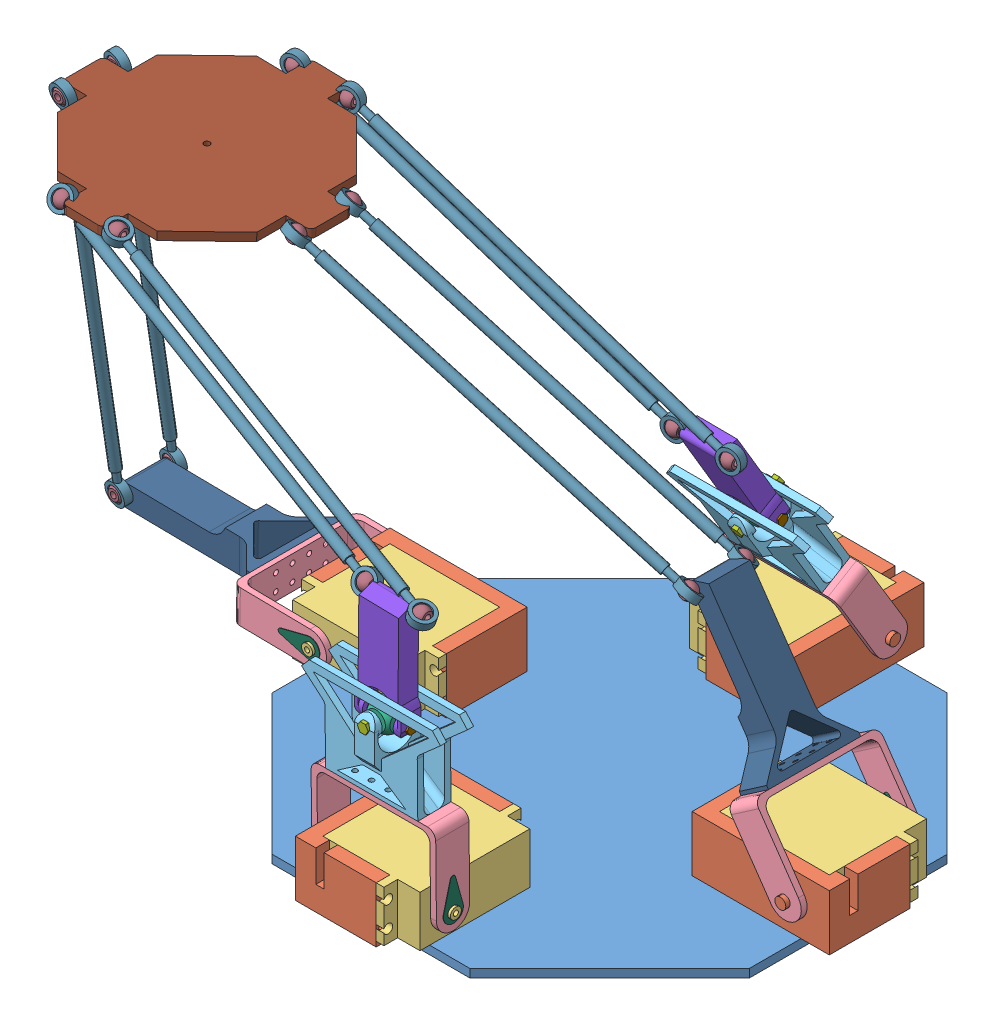
SolidWorks assembly asm(backup2), configuration 기본. Lengths in mm.
Overall size (442.04 257.52 321.27).
66 component instances, 15 part files, 154 mates.
Components (placement in the parent):
- delta_base_-1: delta_base_ [기본] at (16.2815 -22.3997 221) size (287.2 5 287.2)
- servobracket1_-1: servobracket1_ [기본] at (8418.954 -14.3997 21660.4366) x (0 0 -1) z (0 1 0) size (82.55 54.75 33.48)
- servobracket1_-2: servobracket1_ [기본] at (-21423.155 -14.3997 8623.6725) x (1 0 0) z (0 1 0) size (82.55 54.75 33.48)
- servobracket1_-3: servobracket1_ [기본] at (-8386.3909 -14.3997 -21218.4366) x (0 0 1) z (0 1 0) size (82.55 54.75 33.48)
- servobracket1_-4: servobracket1_ [기본] at (21455.7181 -14.3997 -8181.6725) x (-1 0 0) z (0 1 0) size (82.55 54.75 33.48)
- servo_drive_HV2060MG-1: servo_drive_HV2060MG [기본] at (-103.0792 0.8403 200.815) x (-1 0 0) z (0 0 1) size (82.55 30.48 64.98)
- servo_drive_HV2060MG-2: servo_drive_HV2060MG [기본] at (36.4665 0.8403 101.6393) x (0 0 -1) z (-1 0 0) size (82.55 30.48 64.98)
- servo_drive_HV2060MG-3: servo_drive_HV2060MG [기본] at (135.6423 0.8403 241.185) x (1 0 0) z (0 0 -1) size (82.55 30.48 64.98)
- servo_drive_HV2060MG-4: servo_drive_HV2060MG [기본] at (-3.9035 0.8403 340.3607) x (0 0 1) z (1 0 0) size (82.55 30.48 64.98)
- servobracket2_-1: servobracket2_ [기본] at (20.8415 47.838 358.7486) x (1 0 0) z (0 0.009952 -0.99995) size (75 57 20)
- servobracket2_-2: servobracket2_ [기본] at (11.7215 41.0925 107.9835) x (-1 0 0) z (0 -0.516264 0.85643) size (75 57 20)
- univ_link1-1: univ_link1 [기본] at (14.8415 70.128 358.9705) x (0 -0.009952 0.99995) z (1 0 0) size (28.84 52.05 83.6)
- univ_link1-2: univ_link1 [기본] at (5.7215 60.1833 119.4916) x (0 -0.516264 0.85643) z (1 0 0) size (28.84 52.05 83.6)
- ball-1: ball [기본] at (20.8415 85.1323 359.1198) x (-0.999788 0.020606 0.000205) z (0 0.009952 -0.99995) size (24 24 18)
- ball-2: ball [기본] at (11.7215 73.034 127.2381) x (0.999789 -0.017578 -0.010596) z (0 -0.516264 0.85643) size (24 24 18)
- univ_bolt_-1: univ_bolt_ [기본] at (20.8415 85.2815 344.1207) x (1 0 0) z (0 -0.99995 -0.009952) size (6.46 12 5.59)
- univ_bolt_-2: univ_bolt_ [기본] at (11.7215 65.29 140.0848) x (0.5 -0.74169 -0.447097) z (0.866025 0.428215 0.258132) size (6.46 12 5.59)
- univ_bolt_-3: univ_bolt_ [기본] at (20.8415 84.983 374.1193) x (1 0 0) z (0 0.99995 0.009952) size (6.46 12 5.59)
- univ_bolt_-4: univ_bolt_ [기본] at (11.7215 80.7779 114.3919) x (0.5 0.74169 0.447097) z (0.866025 -0.428215 -0.258132) size (6.46 12 5.59)
- univ_link2-3: univ_link2 [기본] at (12.0407 82.7718 140.114) x (-0.999789 0.017578 0.010596) z (0 0.516264 -0.85643) size (28.56 68.77 12)
- univ_bolt2_-1: univ_bolt2_ [기본] at (26.7297 72.7702 127.0791) x (0 -0.516264 0.85643) z (-0.020525 -0.856249 -0.516155) size (6.46 12 5.59)
- univ_bolt2_-2: univ_bolt2_ [기본] at (-3.264 73.2975 127.397) x (0 0.516264 -0.85643) z (-0.020525 -0.856249 -0.516155) size (6.46 12 5.59)
- univ_link2-4: univ_link2 [기본] at (21.1615 100.1783 353.2692) x (0.999788 -0.020606 -0.000205) z (0 -0.009952 0.99995) size (28.56 68.77 12)
- univ_bolt2_-3: univ_bolt2_ [기본] at (5.856 85.4411 359.1229) x (0 0.009952 -0.99995) z (-0.020607 -0.999738 -0.00995) size (6.46 12 5.59)
- univ_bolt2_-4: univ_bolt2_ [기본] at (35.8496 84.823 359.1167) x (0 -0.009952 0.99995) z (-0.020607 -0.999738 -0.00995) size (6.46 12 5.59)
- servobracket2_-3: servobracket2_ [기본] at (-167.995 1.4804 225.56) x (0 0 1) z (0.013619 0.999907 0) size (75 57 20)
- servobracket2_-4: servobracket2_ [기본] at (126.8456 39.5083 216.44) x (0 0 -1) z (-0.822723 -0.568443 0) size (75 57 20)
- link1_-1: link1_ [기본] at (118.6184 33.8239 244.19) x (0 0 -1) z (0.568443 -0.822723 0) size (55.5 20 93)
- link1_-2: link1_ [기본] at (-167.8588 11.4795 197.81) x (0 0 1) z (0.999907 -0.013619 0) size (55.5 20 93)
- delta_end_-1: delta_end_ [기본] at (-187.6375 228.1369 259.3603) x (-0.999789 0.020532 0) z (0 0 1) size (150 5 150)
- link_bridge_-1: link_bridge_ [기본] at (75.6845 113.5552 216.4377) x (-1 0 0) z (0 1 0) size (4.5 28.5 4.5)
- bearing-1: bearing [기본] at (75.6845 113.5552 200.0127) x (0 1 0) z (1 0 0) size (9.35 6.85 9.35)
- link_bridge_-2: link_bridge_ [기본] at (-117.7035 224.2001 259.3603) x (0.013819 0.999905 0) z (0.999905 -0.013819 0) size (4.5 28.5 4.5)
- bearing-2: bearing [기본] at (-117.7035 224.2001 242.9353) x (0.999983 -0.005841 0) z (-0.005841 -0.999983 0) size (9.35 6.85 9.35)
- bearing-3: bearing [기본] at (75.6845 113.5552 232.8627) x (1 0 0) z (0 -1 0) size (9.35 6.85 9.35)
- bearing-4: bearing [기본] at (-117.7035 224.2001 275.7853) x (0 -1 0) z (1 0 0) size (9.35 6.85 9.35)
- rod-1: rod [기본] at (75.6845 113.5552 232.8627) x (-0.447003 -0.491287 -0.747547) z (-0.852305 0.487638 0.18917) size (13.45 6 240.35)
- rod-2: rod [기본] at (-117.7035 224.2001 242.9353) x (0.430843 0.449472 0.782527) z (0.852305 -0.487638 -0.18917) size (13.45 6 240.35)
- link_bridge_-3: link_bridge_ [기본] at (-257.674 227.0746 259.3603) x (0.064888 0.997893 0) z (0.997893 -0.064888 0) size (4.5 28.5 4.5)
- bearing-5: bearing [기본] at (-257.674 227.0746 275.7853) x (-0.114329 0.993443 0) z (-0.993443 -0.114329 0) size (9.35 6.85 9.35)
- bearing-6: bearing [기본] at (-257.674 227.0746 242.9353) x (1 0 0) z (0 -1 0) size (9.35 6.85 9.35)
- link_bridge_-4: link_bridge_ [기본] at (-257.9888 2.7062 225.5623) x (1 0 0) z (0 -1 0) size (4.5 28.5 4.5)
- bearing-7: bearing [기본] at (-257.9888 2.7062 209.1373) x (1 0 0) z (0 -1 0) size (9.35 6.85 9.35)
- bearing-8: bearing [기본] at (-257.9888 2.7062 241.9873) x (-1 0 0) z (0 -1 0) size (9.35 6.85 9.35)
- rod-3: rod [기본] at (-257.674 227.0746 242.9353) x (0.986649 -0.025612 0.160834) z (-0.001387 -0.988843 -0.148956) size (13.45 6 240.35)
- rod-4: rod [기본] at (-257.9888 2.7062 241.9873) x (-0.992547 0.019512 -0.120288) z (0.001387 0.988843 0.148956) size (13.45 6 240.35)
- link_bridge_-5: link_bridge_ [기본] at (-187.6888 225.6374 189.3603) x (0.020532 0.999789 0) z (0 0 1) size (4.5 28.5 4.5)
- link_bridge_-6: link_bridge_ [기본] at (12.4542 122.668 160.6609) x (0.019047 0.986952 0.159885) z (-0.007648 0.160053 -0.987079) size (4.5 28.5 4.5)
- bearing-9: bearing [기본] at (-204.1103 225.9746 189.3603) x (-0.000218 -0.010596 -0.999944) z (-0.020531 -0.999733 0.010598) size (9.35 6.85 9.35)
- bearing-10: bearing [기본] at (-171.2673 225.3002 189.3603) x (0.017394 0.846974 0.531349) z (-0.01091 -0.531237 0.847153) size (9.35 6.85 9.35)
- bearing-11: bearing [기본] at (-3.9673 122.9568 160.8349) x (-0.019047 -0.986952 -0.159885) z (0.007648 -0.160053 0.987079) size (9.35 6.85 9.35)
- bearing-12: bearing [기본] at (28.8758 122.3793 160.4868) x (0.019047 0.986952 0.159885) z (0.007648 -0.160053 0.987079) size (9.35 6.85 9.35)
- rod-5: rod [기본] at (-204.1103 225.9746 189.3603) x (0.449518 0.89099 -0.0638) z (0.882076 -0.454023 -0.125718) size (13.45 6 240.35)
- rod-6: rod [기본] at (28.8758 122.3793 160.4868) x (-0.439311 -0.889519 0.125547) z (-0.882076 0.453596 0.127252) size (13.45 6 240.35)
- link_bridge_-8: link_bridge_ [기본] at (22.5897 144.9013 356.7145) x (0.020602 0.999328 0.030308) z (-0.00042 -0.030306 0.999541) size (4.5 28.5 4.5)
- bearing-13: bearing [기본] at (39.0112 144.5628 356.7111) x (0.020037 0.969771 0.243194) z (-0.004812 -0.243147 0.969978) size (9.35 6.85 9.35)
- bearing-15: bearing [기본] at (6.1682 145.2397 356.7179) x (-0.020602 -0.999327 -0.03034) z (-0.00042 -0.030338 0.99954) size (9.35 6.85 9.35)
- rod-8: rod [기본] at (39.0112 144.5628 356.7111) x (-0.131805 -0.007485 0.991247) z (-0.926745 0.355828 -0.120541) size (13.45 6 240.35)
- rod-9: rod [기본] at (6.1682 145.2397 356.7179) x (-0.362907 -0.764853 0.532257) z (-0.926745 0.355817 -0.120571) size (13.45 6 240.35)
- servobracket3_-2: servobracket3_ [기본] at (153.5748 0.8403 177.7076) x (-0.822723 -0.568443 0) z (-0.568443 0.822723 0) size (12 5 24.89)
- servobracket3_-3: servobracket3_ [기본] at (54.5739 0.8403 358.2932) x (0 -0.009952 0.99995) z (0 0.99995 0.009952) size (12 5 24.89)
- servobracket3_-4: servobracket3_ [기본] at (-22.0109 0.8403 83.7068) x (0 0.516264 -0.85643) z (0 0.85643 0.516264) size (12 5 24.89)
- servobracket3_-5: servobracket3_ [기본] at (-121.0117 0.8403 259.2924) x (-0.013619 -0.999907 0) z (-0.999907 0.013619 0) size (12 5 24.89)
- link_bridge_-9: link_bridge_ [기본] at (-187.6888 225.6374 329.3603) x (0.020532 0.999789 0) z (0 0 -1) size (4.5 28.5 4.5)
- bearing-17: bearing [기본] at (-171.2673 225.3002 329.3603) x (0.019936 0.97077 0.239183) z (0.004911 0.239133 -0.970974) size (9.35 6.85 9.35)
- bearing-18: bearing [기본] at (-204.1103 225.9746 329.3603) x (0.018656 0.908414 0.417655) z (-0.008575 -0.417567 0.908606) size (9.35 6.85 9.35)
Mates (geometry in assembly coordinates):
- 동심1: concentric anti-aligned: cylinder of delta_base_-1 through (11.2815 -17.3997 82.46) axis (0 -1 0) radius 1.5; cylinder of servobracket1_-1 through (11.2815 -17.3997 82.46) axis (0 1 0) radius 1.5
- 동심2: concentric anti-aligned: cylinder of delta_base_-1 through (21.2815 -17.3997 92.46) axis (0 -1 0) radius 1.5; cylinder of servobracket1_-1 through (21.2815 -17.3997 92.46) axis (0 1 0) radius 1.5
- 일치1: coincident anti-aligned: plane of delta_base_-1 through (16.2815 -17.3997 221) normal (0 1 0); plane of servobracket1_-1 through (8418.954 -17.3997 21660.4366) normal (0 -1 0)
- 동심3: concentric anti-aligned: cylinder of delta_base_-1 through (154.8215 -17.3997 216) axis (0 -1 0) radius 1.5; cylinder of servobracket1_-2 through (154.8215 -17.3997 216) axis (0 1 0) radius 1.5
- 동심4: concentric anti-aligned: cylinder of delta_base_-1 through (144.8215 -17.3997 226) axis (0 -1 0) radius 1.5; cylinder of servobracket1_-2 through (144.8215 -17.3997 226) axis (0 1 0) radius 1.5
- 일치4: coincident anti-aligned: plane of delta_base_-1 through (16.2815 -17.3997 221) normal (0 1 0); plane of servobracket1_-2 through (-21423.155 -17.3997 8623.6725) normal (0 -1 0)
- 동심5: concentric anti-aligned: cylinder of delta_base_-1 through (21.2815 -17.3997 359.54) axis (0 -1 0) radius 1.5; cylinder of servobracket1_-3 through (21.2815 -17.3997 359.54) axis (0 1 0) radius 1.5
- 동심6: concentric anti-aligned: cylinder of delta_base_-1 through (11.2815 -17.3997 349.54) axis (0 -1 0) radius 1.5; cylinder of servobracket1_-3 through (11.2815 -17.3997 349.54) axis (0 1 0) radius 1.5
- 일치5: coincident anti-aligned: plane of delta_base_-1 through (16.2815 -17.3997 221) normal (0 1 0); plane of servobracket1_-3 through (-8386.3909 -17.3997 -21218.4366) normal (0 -1 0)
- 동심7: concentric anti-aligned: cylinder of delta_base_-1 through (-122.2585 -17.3997 226) axis (0 -1 0) radius 1.5; cylinder of servobracket1_-4 through (-122.2585 -17.3997 226) axis (0 1 0) radius 1.5
- 동심8: concentric anti-aligned: cylinder of delta_base_-1 through (-112.2585 -17.3997 216) axis (0 -1 0) radius 1.5; cylinder of servobracket1_-4 through (-112.2585 -17.3997 216) axis (0 1 0) radius 1.5
- 일치6: coincident anti-aligned: plane of delta_base_-1 through (16.2815 -17.3997 221) normal (0 1 0); plane of servobracket1_-4 through (21455.7181 -17.3997 -8181.6725) normal (0 -1 0)
- 일치7: coincident anti-aligned: plane of servobracket1_-4 through (-70.0592 16.0803 241.1804) normal (-1 0 0); plane of servo_drive_HV2060MG-1 through (-70.0592 16.0803 241.1904) normal (1 0 0)
- 일치8: coincident anti-aligned: plane of servobracket1_-4 through (-70.0592 16.0803 200.815) normal (0 0 1); plane of servo_drive_HV2060MG-1 through (-103.0792 0.8403 200.815) normal (0 0 -1)
- 일치9: coincident anti-aligned: plane of servobracket1_-4 through (21455.7181 -14.3997 -8181.6725) normal (0 1 0); plane of servo_drive_HV2060MG-1 through (-136.0992 -14.3997 241.1904) normal (0 -1 0)
- 일치10: coincident anti-aligned: plane of servobracket1_-1 through (-3.8989 16.0803 134.6593) normal (0 0 -1); plane of servo_drive_HV2060MG-2 through (-3.9089 16.0803 134.6593) normal (0 0 1)
- 일치11: coincident anti-aligned: plane of servobracket1_-1 through (36.4665 16.0803 134.6593) normal (-1 0 0); plane of servo_drive_HV2060MG-2 through (36.4665 0.8403 101.6393) normal (1 0 0)
- 일치12: coincident anti-aligned: plane of servobracket1_-1 through (8418.954 -14.3997 21660.4366) normal (0 1 0); plane of servo_drive_HV2060MG-2 through (-3.9089 -14.3997 68.6193) normal (0 -1 0)
- 일치13: coincident anti-aligned: plane of servobracket1_-2 through (102.6223 16.0803 200.8196) normal (1 0 0); plane of servo_drive_HV2060MG-3 through (102.6223 16.0803 200.8096) normal (-1 0 0)
- 일치14: coincident anti-aligned: plane of servobracket1_-2 through (102.6223 16.0803 241.185) normal (0 0 -1); plane of servo_drive_HV2060MG-3 through (135.6423 0.8403 241.185) normal (0 0 1)
- 일치15: coincident anti-aligned: plane of servobracket1_-2 through (-21423.155 -14.3997 8623.6725) normal (0 1 0); plane of servo_drive_HV2060MG-3 through (168.6623 -14.3997 200.8096) normal (0 -1 0)
- 일치16: coincident anti-aligned: plane of servobracket1_-3 through (36.4619 16.0803 307.3407) normal (0 0 1); plane of servo_drive_HV2060MG-4 through (36.4719 16.0803 307.3407) normal (0 0 -1)
- 일치17: coincident anti-aligned: plane of servobracket1_-3 through (-3.9035 16.0803 307.3407) normal (1 0 0); plane of servo_drive_HV2060MG-4 through (-3.9035 0.8403 340.3607) normal (-1 0 0)
- 일치18: coincident anti-aligned: plane of servobracket1_-3 through (-8386.3909 -14.3997 -21218.4366) normal (0 1 0); plane of servo_drive_HV2060MG-4 through (36.4719 -14.3997 373.3807) normal (0 -1 0)
- 동심12: concentric aligned: circle of servobracket1_-3; cylinder of servobracket2_-1 through (-12.1585 0.8403 358.2809) axis (-1 0 0) radius 3.3
- 일치19: coincident anti-aligned: plane of servobracket1_-3 through (-12.1585 16.0803 381.6357) normal (-1 0 0); plane of servobracket2_-1 through (-12.1585 -9.2587 368.1809) normal (1 0 0)
- 동심13: concentric aligned: circle of servobracket1_-1; cylinder of servobracket2_-2 through (44.7215 0.8403 83.7191) axis (1 0 0) radius 3.3
- 일치20: coincident anti-aligned: plane of servobracket1_-1 through (44.7215 16.0803 60.3643) normal (1 0 0); plane of servobracket2_-2 through (44.7215 -2.5613 69.9922) normal (-1 0 0)
- 동심14: concentric anti-aligned: cylinder of servobracket2_-1 through (15.8415 45.7884 363.7285) axis (0 0.99995 0.009952) radius 1.5; cylinder of univ_link1-1 through (15.8415 50.7881 363.7782) axis (0 -0.99995 -0.009952) radius 1.5
- 동심15: concentric anti-aligned: cylinder of servobracket2_-1 through (25.8415 45.8879 353.729) axis (0 0.99995 0.009952) radius 1.5; cylinder of univ_link1-1 through (25.8415 50.8876 353.7787) axis (0 -0.99995 -0.009952) radius 1.5
- 일치22: coincident anti-aligned: plane of servobracket2_-1 through (20.8415 47.838 358.7486) normal (0 0.99995 0.009952); plane of univ_link1-1 through (-6.9085 47.7385 368.7481) normal (0 -0.99995 -0.009952)
- 동심16: concentric anti-aligned: cylinder of servobracket2_-2 through (6.7215 36.7984 111.2331) axis (0 0.85643 0.516264) radius 1.5; cylinder of univ_link1-2 through (6.7215 41.0805 113.8144) axis (0 -0.85643 -0.516264) radius 1.5
- 동심17: concentric anti-aligned: cylinder of servobracket2_-2 through (16.7215 41.961 102.6688) axis (0 0.85643 0.516264) radius 1.5; cylinder of univ_link1-2 through (16.7215 46.2432 105.2502) axis (0 -0.85643 -0.516264) radius 1.5
- 일치23: coincident anti-aligned: plane of servobracket2_-2 through (11.7215 41.0925 107.9835) normal (0 0.85643 0.516264); plane of univ_link1-2 through (-16.0285 35.9299 116.5478) normal (0 -0.85643 -0.516264)
- 일치24: coincident anti-aligned: circle of univ_link1-1; circle of ball-1
- 일치26: coincident anti-aligned: plane of univ_link1-1 through (22.4565 82.4645 346.0928) normal (0 0.99995 0.009952); plane of univ_bolt_-1 through (19.2265 82.4645 346.0928) normal (0 -0.99995 -0.009952)
- 동심18: concentric aligned: cylinder of ball-1 through (20.8415 85.0626 366.1195) axis (0 0.009952 -0.99995) radius 1.55; cylinder of univ_bolt_-1 through (20.8415 85.1621 356.1202) axis (0 0.009952 -0.99995) radius 1.55
- 일치27: coincident anti-aligned: plane of univ_link1-1 through (14.8415 70.2574 345.9713) normal (0 0.009952 -0.99995); plane of univ_bolt_-1 through (20.8415 85.2616 346.1206) normal (0 -0.009952 0.99995)
- 일치28: coincident anti-aligned: plane of univ_link1-2 through (10.1065 63.9268 136.9278) normal (0 0.85643 0.516264); plane of univ_bolt_-2 through (13.3365 63.9268 136.9278) normal (0 -0.85643 -0.516264)
- 동심19: concentric aligned: cylinder of ball-2 through (11.7215 76.6479 121.2431) axis (0 -0.516264 0.85643) radius 1.55; cylinder of univ_bolt_-2 through (11.7215 71.4851 129.8076) axis (0 -0.516264 0.85643) radius 1.55
- 일치29: coincident anti-aligned: plane of univ_link1-2 through (5.7215 53.4717 130.6253) normal (0 -0.516264 0.85643); plane of univ_bolt_-2 through (11.7215 66.3225 138.3719) normal (0 0.516264 -0.85643)
- 동심20: concentric anti-aligned: cylinder of ball-1 through (20.8415 85.0626 366.1195) axis (0 0.009952 -0.99995) radius 1.55; cylinder of univ_bolt_-3 through (20.8415 85.1024 362.1199) axis (0 -0.009952 0.99995) radius 1.55
- 일치30: coincident anti-aligned: plane of univ_link1-1 through (19.2265 82.2058 372.0915) normal (0 0.99995 0.009952); plane of univ_bolt_-3 through (22.4565 82.2058 372.0915) normal (0 -0.99995 -0.009952)
- 일치31: coincident anti-aligned: plane of univ_link1-1 through (14.8415 69.9986 371.97) normal (0 -0.009952 0.99995); plane of univ_bolt_-3 through (20.8415 85.0029 372.1194) normal (0 0.009952 -0.99995)
- 일치32: coincident anti-aligned: plane of univ_link1-2 through (13.3365 77.3497 114.6606) normal (0 0.85643 0.516264); plane of univ_bolt_-4 through (10.1065 77.3497 114.6606) normal (0 -0.85643 -0.516264)
- 동심21: concentric anti-aligned: cylinder of ball-2 through (11.7215 76.6479 121.2431) axis (0 -0.516264 0.85643) radius 1.55; cylinder of univ_bolt_-4 through (11.7215 74.5827 124.669) axis (0 0.516264 -0.85643) radius 1.55
- 일치33: coincident anti-aligned: plane of univ_link1-2 through (5.7215 66.8946 108.3582) normal (0 0.516264 -0.85643); plane of univ_bolt_-4 through (11.7215 79.7454 116.1047) normal (0 -0.516264 0.85643)
- 일치35: coincident aligned: plane of ball-2; plane of univ_link2-3
- 일치37: coincident anti-aligned: plane of univ_link2-3; plane of univ_bolt2_-1
- 일치38: coincident anti-aligned: plane of ball-2 through (2.7542 75.251 126.8231) normal (0 -0.516264 0.85643); plane of univ_bolt2_-1 through (14.763 75.0399 126.6958) normal (0 0.516264 -0.85643)
- 일치39: coincident anti-aligned: plane of ball-2 through (2.6926 71.1335 127.8439) normal (0.020525 0.856249 0.516155); plane of univ_bolt2_-1 through (14.7014 72.4711 125.1473) normal (-0.020525 -0.856249 -0.516155)
- 일치40: coincident anti-aligned: plane of univ_link2-3; plane of univ_bolt2_-1
- 일치126: coincident aligned: circle of univ_link1-2; circle of ball-2
- 일치44: coincident anti-aligned: plane of univ_link2-3; plane of univ_bolt2_-2
- 일치45: coincident anti-aligned: plane of ball-2 through (2.7542 73.7022 129.3924) normal (0 0.516264 -0.85643); plane of univ_bolt2_-2 through (8.7642 73.5965 129.3287) normal (0 -0.516264 0.85643)
- 일치46: coincident anti-aligned: plane of ball-2 through (2.6926 71.1335 127.8439) normal (0.020525 0.856249 0.516155); plane of univ_bolt2_-2 through (8.7027 71.0278 127.7802) normal (-0.020525 -0.856249 -0.516155)
- 일치47: coincident anti-aligned: plane of univ_link2-3; plane of univ_bolt2_-2
- 일치49: coincident aligned: plane of ball-1 through (29.8705 86.4315 360.6328) normal (0 0.009952 -0.99995); plane of univ_link2-4 through (6.4664 86.9111 360.6376) normal (0 0.009952 -0.99995)
- 일치50: coincident anti-aligned: plane of univ_link2-4 through (7.9132 88.2562 353.1506) normal (-0.020607 -0.999738 -0.00995); plane of univ_bolt2_-3 through (7.9132 88.2125 357.5354) normal (0.020607 0.999738 0.00995)
- 일치51: coincident anti-aligned: plane of ball-1 through (29.8705 86.4315 360.6328) normal (0 0.009952 -0.99995); plane of univ_bolt2_-3 through (17.8844 86.6785 360.6353) normal (0 -0.009952 0.99995)
- 일치52: coincident anti-aligned: plane of ball-1 through (29.8087 83.4621 357.6031) normal (0.020607 0.999738 0.00995); plane of univ_bolt2_-3 through (17.8225 83.6793 360.6054) normal (-0.020607 -0.999738 -0.00995)
- 일치53: coincident anti-aligned: plane of univ_link2-4 through (8.1645 100.4462 353.2719) normal (-0.999788 0.020606 0.000205); plane of univ_bolt2_-3 through (7.8556 85.3999 359.1225) normal (0.999788 -0.020606 -0.000205)
- 일치54: coincident anti-aligned: plane of univ_link2-4 through (33.9077 87.6768 357.5285) normal (-0.020607 -0.999738 -0.00995); plane of univ_bolt2_-4 through (33.9077 87.6446 360.7599) normal (0.020607 0.999738 0.00995)
- 일치55: coincident anti-aligned: plane of ball-1 through (29.8705 86.4614 357.633) normal (0 -0.009952 0.99995); plane of univ_bolt2_-4 through (23.8831 86.5848 357.6342) normal (0 0.009952 -0.99995)
- 일치56: coincident anti-aligned: plane of ball-1 through (29.8087 83.4621 357.6031) normal (0.020607 0.999738 0.00995); plane of univ_bolt2_-4 through (23.8213 83.5855 357.6043) normal (-0.020607 -0.999738 -0.00995)
- 일치57: coincident anti-aligned: plane of univ_link2-4 through (34.159 99.9104 353.2666) normal (0.999788 -0.020606 -0.000205); plane of univ_bolt2_-4 through (33.8501 84.8642 359.1171) normal (-0.999788 0.020606 0.000205)
- 동심22: concentric aligned: circle of servobracket1_-4; cylinder of servobracket2_-3 through (-120.9993 0.8403 192.56) axis (0 0 -1) radius 3.3
- 일치58: coincident anti-aligned: plane of servobracket1_-4 through (-144.3542 16.0803 192.56) normal (0 0 -1); plane of servobracket2_-3 through (-111.1365 -9.2949 192.56) normal (0 0 1)
- 동심23: concentric aligned: circle of servobracket1_-2; cylinder of servobracket2_-4 through (153.5624 0.8403 249.44) axis (0 0 1) radius 3.3
- 일치59: coincident anti-aligned: plane of servobracket1_-2 through (176.9173 16.0803 249.44) normal (0 0 1); plane of servobracket2_-4 through (167.4741 -1.7025 249.44) normal (0 0 -1)
- 동심24: concentric anti-aligned: cylinder of servobracket2_-4 through (132.0961 40.7051 221.44) axis (-0.568443 0.822723 0) radius 1.5; cylinder of link1_-1 through (128.117 46.4641 221.44) axis (0.568443 -0.822723 0) radius 1.5
- 동심25: concentric anti-aligned: cylinder of servobracket2_-4 through (123.8689 35.0207 211.44) axis (-0.568443 0.822723 0) radius 1.5; cylinder of link1_-1 through (119.8898 40.7797 211.44) axis (0.568443 -0.822723 0) radius 1.5
- 일치60: coincident anti-aligned: plane of servobracket2_-4 through (126.8456 39.5083 216.44) normal (-0.568443 0.822723 0); plane of link1_-1 through (135.0728 45.1927 188.69) normal (0.568443 -0.822723 0)
- 동심26: concentric anti-aligned: cylinder of servobracket2_-3 through (-166.0633 -3.5463 230.56) axis (-0.999907 0.013619 0) radius 1.5; cylinder of link1_-2 through (-173.0626 -3.451 230.56) axis (0.999907 -0.013619 0) radius 1.5
- 동심27: concentric anti-aligned: cylinder of servobracket2_-3 through (-165.9271 6.4527 220.56) axis (-0.999907 0.013619 0) radius 1.5; cylinder of link1_-2 through (-172.9264 6.5481 220.56) axis (0.999907 -0.013619 0) radius 1.5
- 일치61: coincident anti-aligned: plane of servobracket2_-3 through (-167.995 1.4804 225.56) normal (-0.999907 0.013619 0); plane of link1_-2 through (-168.1312 -8.5186 253.31) normal (0.999907 -0.013619 0)
- 동심29: concentric anti-aligned: cylinder of link1_-1 through (75.6845 113.5552 188.69) axis (0 0 1) radius 2.15; cylinder of link_bridge_-1 through (75.6845 113.5552 228.9377) axis (0 0 -1) radius 2
- 일치66: coincident anti-aligned: plane of link1_-1 through (83.913 119.2378 228.9377) normal (0 0 1); plane of link_bridge_-1 through (75.6845 113.5552 228.9377) normal (0 0 -1)
- 일치68: coincident anti-aligned: plane of link_bridge_-1 through (75.6845 113.5552 203.4377) normal (0 0 -1); plane of bearing-1 through (75.6845 113.5552 203.4377) normal (0 0 1)
- 동심30: concentric aligned: cylinder of link_bridge_-1 through (75.6845 113.5552 202.1877) axis (0 0 1) radius 1.775; cylinder of bearing-1 through (75.6845 113.5552 196.5877) axis (0 0 1) radius 1.775
- 동심31: concentric anti-aligned: cylinder of delta_end_-1 through (-117.7035 224.2001 184.3603) axis (0 0 1) radius 2; cylinder of link_bridge_-2 through (-117.7035 224.2001 271.8603) axis (0 0 -1) radius 2
- 일치70: coincident anti-aligned: plane of delta_end_-1 through (-187.7401 223.1379 271.8603) normal (0 0 1); plane of link_bridge_-2 through (-117.7035 224.2001 271.8603) normal (0 0 -1)
- 동심32: concentric aligned: cylinder of link_bridge_-2 through (-117.7035 224.2001 245.1103) axis (0 0 1) radius 1.775; cylinder of bearing-2 through (-117.7035 224.2001 239.5103) axis (0 0 1) radius 1.775
- 일치71: coincident anti-aligned: plane of link_bridge_-2 through (-117.7035 224.2001 246.3603) normal (0 0 -1); plane of bearing-2 through (-117.7035 224.2001 246.3603) normal (0 0 1)
- 동심35: concentric anti-aligned: cylinder of link_bridge_-1 through (75.6845 113.5552 230.6877) axis (0 0 -1) radius 1.775; cylinder of bearing-3 through (75.6845 113.5552 229.4377) axis (0 0 1) radius 1.775
- 일치76: coincident anti-aligned: plane of link_bridge_-1 through (75.6845 113.5552 229.4377) normal (0 0 1); plane of bearing-3 through (75.6845 113.5552 229.4377) normal (0 0 -1)
- 일치78: coincident anti-aligned: plane of link_bridge_-2 through (-117.7035 224.2001 272.3603) normal (0 0 1); plane of bearing-4 through (-117.7035 224.2001 272.3603) normal (0 0 -1)
- 동심36: concentric aligned: cylinder of link_bridge_-2 through (-117.7035 224.2001 273.6103) axis (0 0 -1) radius 1.775; cylinder of bearing-4 through (-117.7035 224.2001 279.2103) axis (0 0 -1) radius 1.775
- 일치79: coincident: sphere of bearing-3; circle of rod-1
- 일치80: coincident: sphere of bearing-4; circle of rod-1
- 일치81: coincident: sphere of bearing-1; circle of rod-2
- 일치82: coincident: sphere of bearing-2; circle of rod-2
- 동심37: concentric anti-aligned: cylinder of delta_end_-1 through (-257.674 227.0746 184.3603) axis (0 0 1) radius 2; cylinder of link_bridge_-3 through (-257.674 227.0746 271.8603) axis (0 0 -1) radius 2
- 일치83: coincident anti-aligned: plane of delta_end_-1 through (-187.7401 223.1379 246.8603) normal (0 0 -1); plane of link_bridge_-3 through (-257.674 227.0746 246.8603) normal (0 0 1)
- 동심38: concentric aligned: cylinder of link_bridge_-3 through (-257.674 227.0746 273.6103) axis (0 0 -1) radius 1.775; cylinder of bearing-5 through (-257.674 227.0746 279.2103) axis (0 0 -1) radius 1.775
- 일치84: coincident anti-aligned: plane of link_bridge_-3 through (-257.674 227.0746 272.3603) normal (0 0 1); plane of bearing-5 through (-257.674 227.0746 272.3603) normal (0 0 -1)
- 동심39: concentric aligned: cylinder of link_bridge_-3 through (-257.674 227.0746 245.1103) axis (0 0 1) radius 1.775; cylinder of bearing-6 through (-257.674 227.0746 239.5103) axis (0 0 1) radius 1.775
- 일치85: coincident anti-aligned: plane of link_bridge_-3 through (-257.674 227.0746 246.3603) normal (0 0 -1); plane of bearing-6 through (-257.674 227.0746 246.3603) normal (0 0 1)
- 동심40: concentric aligned: cylinder of link1_-2 through (-257.9888 2.7062 253.31) axis (0 0 -1) radius 2.15; cylinder of link_bridge_-4 through (-257.9888 2.7062 238.0623) axis (0 0 -1) radius 2
- 일치86: coincident anti-aligned: plane of link1_-2 through (-258.1228 -7.2929 213.0623) normal (0 0 -1); plane of link_bridge_-4 through (-257.9888 2.7062 213.0623) normal (0 0 1)
- 동심41: concentric aligned: cylinder of link_bridge_-4 through (-257.9888 2.7062 211.3123) axis (0 0 1) radius 1.775; cylinder of bearing-7 through (-257.9888 2.7062 205.7123) axis (0 0 1) radius 1.775
- 일치87: coincident anti-aligned: plane of link_bridge_-4 through (-257.9888 2.7062 212.5623) normal (0 0 -1); plane of bearing-7 through (-257.9888 2.7062 212.5623) normal (0 0 1)
- 동심42: concentric aligned: cylinder of link_bridge_-4 through (-257.9888 2.7062 239.8123) axis (0 0 -1) radius 1.775; cylinder of bearing-8 through (-257.9888 2.7062 245.4123) axis (0 0 -1) radius 1.775
- 일치88: coincident anti-aligned: plane of link_bridge_-4 through (-257.9888 2.7062 238.5623) normal (0 0 1); plane of bearing-8 through (-257.9888 2.7062 238.5623) normal (0 0 -1)
- 일치89: coincident: sphere of bearing-7; circle of rod-3
- 일치91: coincident: sphere of bearing-6; circle of rod-3
- 일치93: coincident: sphere of bearing-5; circle of rod-4
- 일치95: coincident: sphere of bearing-8; circle of rod-4
- 동심43: concentric aligned: cylinder of delta_end_-1 through (-262.673 227.1773 189.3603) axis (0.999789 -0.020532 0) radius 2; cylinder of link_bridge_-5 through (-200.1862 225.894 189.3603) axis (0.999789 -0.020532 0) radius 2
- 일치96: coincident anti-aligned: plane of delta_end_-1 through (-175.2428 222.8813 259.3603) normal (0.999789 -0.020532 0); plane of link_bridge_-5 through (-175.1914 225.3807 189.3603) normal (-0.999789 0.020532 0)
- 동심44: concentric aligned: cylinder of univ_link2-3 through (27.3768 122.4057 160.5027) axis (-0.999789 0.017578 0.010596) radius 2; cylinder of link_bridge_-6 through (24.9516 122.4483 160.5284) axis (-0.999789 0.017578 0.010596) radius 2
- 일치97: coincident anti-aligned: plane of univ_link2-3; plane of link_bridge_-6
- 동심45: concentric aligned: cylinder of link_bridge_-5 through (-201.9358 225.93 189.3603) axis (0.999789 -0.020532 0) radius 1.775; cylinder of bearing-9 through (-207.5346 226.045 189.3603) axis (0.999789 -0.020532 0) radius 1.775
- 일치98: coincident anti-aligned: plane of link_bridge_-5 through (-200.6861 225.9043 189.3603) normal (-0.999789 0.020532 0); plane of bearing-9 through (-200.6861 225.9043 189.3603) normal (0.999789 -0.020532 0)
- 동심46: concentric aligned: cylinder of link_bridge_-5 through (-173.4418 225.3448 189.3603) axis (-0.999789 0.020532 0) radius 1.775; cylinder of bearing-10 through (-167.843 225.2298 189.3603) axis (-0.999789 0.020532 0) radius 1.775
- 일치99: coincident anti-aligned: plane of link_bridge_-5 through (-174.6915 225.3705 189.3603) normal (0.999789 -0.020532 0); plane of bearing-10 through (-174.6915 225.3705 189.3603) normal (-0.999789 0.020532 0)
- 동심47: concentric aligned: cylinder of link_bridge_-6 through (-1.7928 122.9185 160.8119) axis (0.999789 -0.017578 -0.010596) radius 1.775; cylinder of bearing-11 through (-7.3916 123.017 160.8712) axis (0.999789 -0.017578 -0.010596) radius 1.775
- 일치100: coincident anti-aligned: plane of link_bridge_-6 through (-0.543 122.8965 160.7986) normal (-0.999789 0.017578 0.010596); plane of bearing-11 through (-0.543 122.8965 160.7986) normal (0.999789 -0.017578 -0.010596)
- 동심48: concentric aligned: cylinder of link_bridge_-6 through (26.7012 122.4175 160.5099) axis (-0.999789 0.017578 0.010596) radius 1.775; cylinder of bearing-12 through (32.3 122.3191 160.4505) axis (-0.999789 0.017578 0.010596) radius 1.775
- 일치101: coincident anti-aligned: plane of link_bridge_-6 through (25.4515 122.4395 160.5231) normal (0.999789 -0.017578 -0.010596); plane of bearing-12 through (25.4515 122.4395 160.5231) normal (-0.999789 0.017578 0.010596)
- 일치102: coincident: sphere of bearing-11; circle of rod-5
- 일치103: coincident: sphere of bearing-9; circle of rod-5
- 일치104: coincident: sphere of bearing-12; circle of rod-6
- 일치107: coincident: sphere of bearing-10; circle of rod-6
- 동심50: concentric aligned: cylinder of univ_link2-4 through (7.6671 145.2088 356.7176) axis (0.999788 -0.020606 -0.000205) radius 2; cylinder of link_bridge_-8 through (10.0923 145.1588 356.7171) axis (0.999788 -0.020606 -0.000205) radius 2
- 일치111: coincident anti-aligned: plane of univ_link2-4 through (10.0923 145.0693 365.7166) normal (-0.999788 0.020606 0.000205); plane of link_bridge_-8 through (10.0923 145.1588 356.7171) normal (0.999788 -0.020606 -0.000205)
- 동심51: concentric aligned: cylinder of link_bridge_-8 through (36.8367 144.6076 356.7116) axis (-0.999788 0.020606 0.000205) radius 1.775; cylinder of bearing-13 through (42.4355 144.4922 356.7104) axis (-0.999788 0.020606 0.000205) radius 1.775
- 일치112: coincident anti-aligned: plane of link_bridge_-8 through (35.5869 144.6334 356.7118) normal (0.999788 -0.020606 -0.000205); plane of bearing-13 through (35.5869 144.6334 356.7118) normal (-0.999788 0.020606 0.000205)
- 동심53: concentric aligned: cylinder of link_bridge_-8 through (8.3427 145.1949 356.7174) axis (0.999788 -0.020606 -0.000205) radius 1.775; cylinder of bearing-15 through (2.7439 145.3103 356.7186) axis (0.999788 -0.020606 -0.000205) radius 1.775
- 일치116: coincident anti-aligned: plane of link_bridge_-8 through (9.5924 145.1691 356.7172) normal (-0.999788 0.020606 0.000205); plane of bearing-15 through (9.5924 145.1691 356.7172) normal (0.999788 -0.020606 -0.000205)
- 일치117: coincident: sphere of bearing-13; circle of rod-8
- 일치120: coincident: sphere of bearing-15; circle of rod-9
- 탄젠트2: tangent: circle of ball-1; plane of univ_link2-4 through (11.5187 81.6334 365.0853) normal (0.999788 -0.020606 -0.000205)
- 동심56: concentric anti-aligned: cylinder of servo_drive_HV2060MG-3 through (153.5748 0.8403 176.2076) axis (0 0 1) radius 3.302; cylinder of servobracket3_-2 through (153.5748 0.8403 182.7076) axis (0 0 -1) radius 3.3
- 일치123: coincident anti-aligned: plane of servo_drive_HV2060MG-3 through (135.6423 0.8403 182.7076) normal (0 0 -1); plane of servobracket3_-2 through (153.5748 0.8403 182.7076) normal (0 0 1)
- 평행1: parallel anti-aligned: plane of servobracket2_-4 through (122.8537 34.8109 181.44) normal (-0.647565 -0.76201 0); plane of servobracket3_-2 through (157.4602 5.4124 182.7076) normal (0.647565 0.76201 0)
- 동심57: concentric aligned: cylinder of servo_drive_HV2060MG-4 through (61.0739 0.8403 358.2932) axis (-1 0 0) radius 3.302; cylinder of servobracket3_-3 through (59.5739 0.8403 358.2932) axis (-1 0 0) radius 3.3
- 일치127: coincident anti-aligned: plane of servo_drive_HV2060MG-4 through (54.5739 0.8403 340.3607) normal (1 0 0); plane of servobracket3_-3 through (54.5739 0.8403 358.2932) normal (-1 0 0)
- 평행2: parallel anti-aligned: plane of servobracket2_-1 through (55.8415 46.3019 352.7786) normal (0 -0.249193 -0.968454); plane of servobracket3_-3 through (59.5739 2.3355 364.104) normal (0 0.249193 0.968454)
- 동심58: concentric aligned: cylinder of servo_drive_HV2060MG-2 through (-28.5109 0.8403 83.7068) axis (1 0 0) radius 3.302; cylinder of servobracket3_-4 through (-27.0109 0.8403 83.7068) axis (1 0 0) radius 3.3
- 일치129: coincident anti-aligned: plane of servo_drive_HV2060MG-2 through (-22.0109 0.8403 101.6393) normal (-1 0 0); plane of servobracket3_-4 through (-22.0109 0.8403 83.7068) normal (1 0 0)
- 평행3: parallel anti-aligned: plane of servobracket2_-2 through (-23.2785 36.6521 112.2594) normal (0 -0.720333 0.693629); plane of servobracket3_-4 through (-27.0109 5.1623 79.545) normal (0 0.720333 -0.693629)
- 동심59: concentric aligned: cylinder of servo_drive_HV2060MG-1 through (-121.0117 0.8403 265.7924) axis (0 0 -1) radius 3.302; cylinder of servobracket3_-5 through (-121.0117 0.8403 264.2924) axis (0 0 -1) radius 3.3
- 일치131: coincident anti-aligned: plane of servo_drive_HV2060MG-1 through (-103.0792 0.8403 259.2924) normal (0 0 1); plane of servobracket3_-5 through (-121.0117 0.8403 259.2924) normal (0 0 -1)
- 평행4: parallel anti-aligned: plane of servobracket2_-3 through (-166.3186 7.4126 260.56) normal (0.27195 0.962311 0); plane of servobracket3_-5 through (-122.6434 -4.9335 264.2924) normal (-0.27195 -0.962311 0)
- 동심60: concentric anti-aligned: cylinder of delta_end_-1 through (-262.673 227.1773 329.3603) axis (0.999789 -0.020532 0) radius 2; cylinder of link_bridge_-9 through (-175.1914 225.3807 329.3603) axis (-0.999789 0.020532 0) radius 2
- 일치132: coincident anti-aligned: plane of delta_end_-1 through (-200.2375 223.3946 259.3603) normal (-0.999789 0.020532 0); plane of link_bridge_-9 through (-200.1862 225.894 329.3603) normal (0.999789 -0.020532 0)
- 동심61: concentric anti-aligned: cylinder of link_bridge_-9 through (-173.4418 225.3448 329.3603) axis (-0.999789 0.020532 0) radius 1.775; cylinder of bearing-17 through (-174.6915 225.3705 329.3603) axis (0.999789 -0.020532 0) radius 1.775
- 일치133: coincident anti-aligned: plane of link_bridge_-9 through (-174.6915 225.3705 329.3603) normal (0.999789 -0.020532 0); plane of bearing-17 through (-174.6915 225.3705 329.3603) normal (-0.999789 0.020532 0)
- 동심62: concentric anti-aligned: cylinder of link_bridge_-9 through (-201.9358 225.93 329.3603) axis (0.999789 -0.020532 0) radius 1.775; cylinder of bearing-18 through (-200.6861 225.9043 329.3603) axis (-0.999789 0.020532 0) radius 1.775
- 일치134: coincident anti-aligned: plane of link_bridge_-9 through (-200.6861 225.9043 329.3603) normal (-0.999789 0.020532 0); plane of bearing-18 through (-200.6861 225.9043 329.3603) normal (0.999789 -0.020532 0)
- 일치136: coincident: circle of rod-8; sphere of bearing-17
- 일치137: coincident: circle of rod-9; sphere of bearing-18
- 탄젠트5: tangent: circle of ball-2; plane of univ_link2-3
